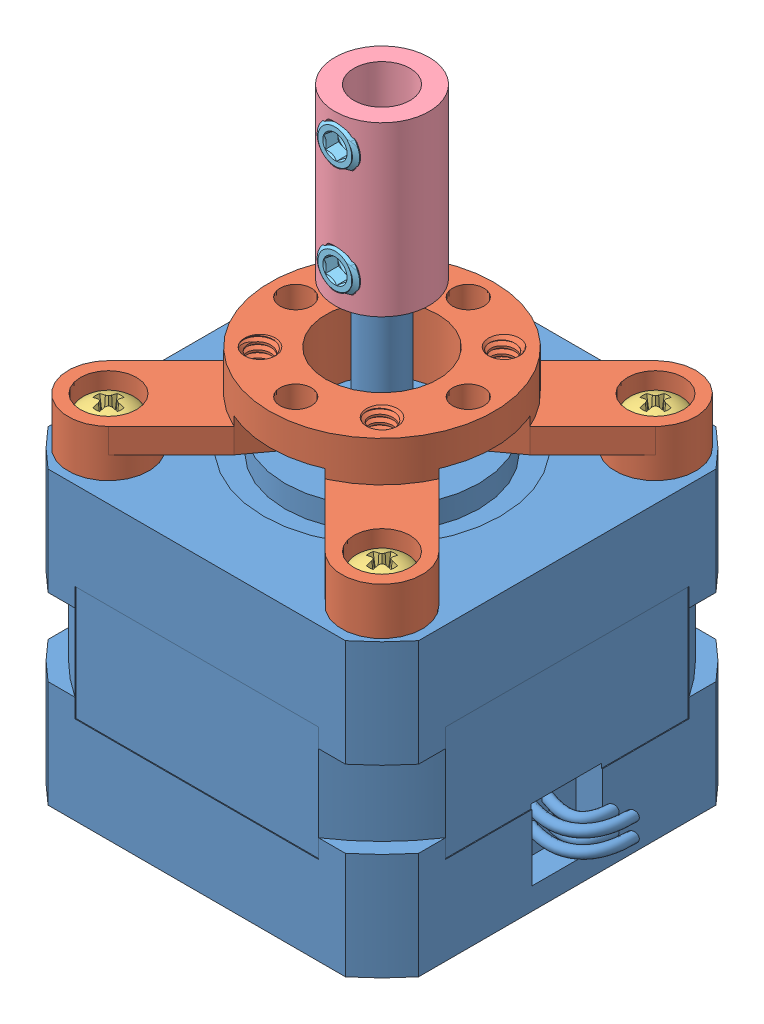
SolidWorks assembly Stepper Motor assem, configuration Default. Lengths in mm.
Overall size (46.31 68.68 42).
11 component instances, 5 part files, 3 mates.
Components (placement in the parent):
- Stepper Motor 9328-1: Stepper Motor 9328 [Default] at origin size (46.31 57.25 42)
- 555152 assembly-1: 555152 assembly [Default] at (-46.3202 49.2232 -16.8805) x (-1 0 0) z (0 0 1) size (40.13 13.81 40.13)
  - 555152-1: 555152 [Default] at (-46.3202 6.3172 16.8805) size (40.13 10.02 40.13)
  - 555152 screw_92005A116-1: 555152 screw_92005A116 [Default] at (-61.8202 19.9372 32.3805) x (1 0 0) z (0 -1 0) size (6 6 8.48)
  - 555152 screw_92005A116-2: 555152 screw_92005A116 [Default] at (-30.8202 19.9372 32.3805) x (0 0 -1) z (0 -1 0) size (6 6 8.48)
  - 555152 screw_92005A116-3: 555152 screw_92005A116 [Default] at (-30.8202 19.9372 1.3805) x (-1 0 0) z (0 -1 0) size (6 6 8.48)
  - 555152 screw_92005A116-4: 555152 screw_92005A116 [Default] at (-61.8202 19.9372 1.3805) x (0 0 1) z (0 -1 0) size (6 6 8.48)
- Motor coupler-1: Motor coupler [Default] at (-58.4931 67.3592 -25.2523) x (-1 0 0) z (0 0 1) size (10.67 19.11 10.81)
  - 625120-1: 625120 [Default] at (-58.4931 -1.3175 25.2523) size (10.67 19.05 10.73)
  - 632134_91375A436-1: 632134_91375A436 [Default] at (-58.4931 14.3035 29.3961) x (0.606109 -0.795381 0) z (0 0 1) size (4.98 4.83 3.31)
  - 632134_91375A436-2: 632134_91375A436 [Default] at (-58.4931 2.1115 29.3961) x (0.605824 -0.795599 0) z (0 0 1) size (4.98 4.83 3.31)
Mates (geometry in assembly coordinates):
- Concentric1: concentric aligned: circle of Stepper Motor 9328-1; circle of 555152 assembly-1/555152-1
- Lock1: lock: unknown of Stepper Motor 9328-1; unknown of 555152 assembly-1/555152-1
- Concentric2: concentric aligned: circle of Stepper Motor 9328-1; circle of Motor coupler-1/625120-1
